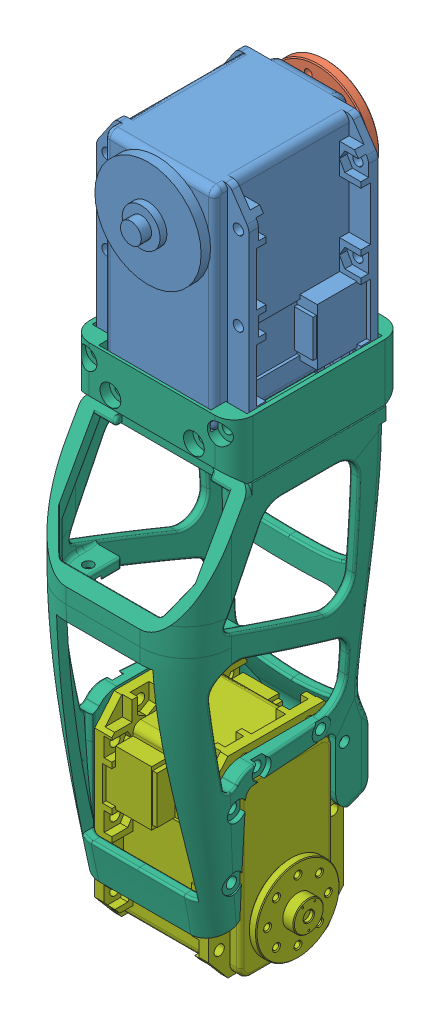
SolidWorks assembly arm_l2, configuration Default. Lengths in mm.
Overall size (45.99 187.91 62.65).
10 component instances, 10 part files, 20 mates.
Components (placement in the parent):
- MX-64T_step-1: MX-64T_step [Default] at (11.6566 50.7443 49.8736) size (40.2 62.1 50)
- HN05-I101_2017-1: HN05-I101_2017 [Default] at (11.6566 50.7443 26.3536) x (-0.978167 -0.207821 0) z (0.207821 -0.978167 0) size (28 3.8 28)
- MF128ZZ_2017-1: MF128ZZ_2017 [Default] at (11.6566 50.7443 30.0736) x (-0.981893 -0.189437 0) z (0.189437 -0.981893 0) size (14 3.48 14)
- RX64-CAP_2017-1: RX64-CAP_2017 [Default] at (11.6566 50.7443 26.5936) x (-0.772804 -0.634645 0) z (0 0 -1) size (9.5 9.5 2.2)
- WB_M2.5X8_2017-1: WB_M2.5X8_2017 [Default] at (11.6566 50.7443 24.2936) x (0 0 1) z (-0.923728 -0.383049 0) size (4.5 4.5 4.5)
- arm_upperarm-1: arm_upperarm [Default] at (-19.8184 -15.6443 22.4331) size (44.79 120.44 61.97)
- MX28_step-1: MX28_step [Default] at (-30.9345 -67.7118 42.6951) x (0 0 1) z (1 0 0) size (35.6 50.71 42.6)
- MX28_HN07-i101-1: MX28_HN07-i101 [Default] at (-8.5434 -105.0057 54.6029) x (0 0.707328 0.706886) z (0 -0.706886 0.707328) size (22 3.05 22)
- MF106ZZ-1: MF106ZZ [Défaut] at (-8.3934 -105.0057 54.6029) x (0 -0.837169 -0.546944) z (0 -0.546944 0.837169) size (11.2 3 11.2)
- RX28-CAP-1: RX28-CAP [Défaut] at (-8.3934 -105.0057 54.6029) x (0 0.357314 -0.933984) z (-1 0 0) size (7.2 7.2 1.8)
Mates (geometry in assembly coordinates):
- Concentric1: concentric aligned: cylinder of MX-64T_step-1 through (11.6566 50.7443 50.9736) axis (0 0 -1) radius 4; cylinder of HN05-I101_2017-1 through (11.6566 50.7443 26.3536) axis (0 0 -1) radius 6
- Coincident1: coincident aligned: cylinder of HN05-I101_2017-1 through (11.6566 50.7443 26.3536) axis (0 0 -1) radius 6; circle of MF128ZZ_2017-1
- Coincident2: coincident anti-aligned: plane of HN05-I101_2017-1 through (5.7876 49.4974 27.3536) normal (0 0 -1); plane of MF128ZZ_2017-1 through (4.7834 49.4183 27.3536) normal (0 0 1)
- Concentric2: concentric aligned: cylinder of MF128ZZ_2017-1 through (11.6566 50.7443 30.0736) axis (0 0 -1) radius 4; cylinder of RX64-CAP_2017-1 through (11.6566 50.7443 27.7936) axis (0 0 -1) radius 4
- Coincident3: coincident anti-aligned: plane of MF128ZZ_2017-1 through (7.7291 49.9866 26.5936) normal (0 0 -1); plane of RX64-CAP_2017-1 through (8.1017 47.825 26.5936) normal (0 0 1)
- Concentric3: concentric aligned: cylinder of RX64-CAP_2017-1 through (11.6566 50.7443 27.7936) axis (0 0 -1) radius 1.55; cylinder of WB_M2.5X8_2017-1 through (11.6566 50.7443 34.7936) axis (0 0 -1) radius 1.25
- Coincident4: coincident anti-aligned: plane of RX64-CAP_2017-1 through (10.3429 49.6654 26.7936) normal (0 0 -1); plane of WB_M2.5X8_2017-1 through (10.7948 52.8227 26.7936) normal (0 0 1)
- Coincident5: coincident anti-aligned: plane of MX-64T_step-1 through (11.6566 50.7443 30.0736) normal (0 0 -1); plane of MF128ZZ_2017-1 through (5.7653 49.6077 30.0736) normal (0 0 1)
- Concentric11: concentric anti-aligned: cylinder of MX-64T_step-1 through (-5.6434 10.7443 62.3736) axis (0 0 -1) radius 1.35; cylinder of arm_upperarm-1 through (-5.6434 10.7443 72.2736) axis (0 0 1) radius 2.75
- Concentric12: concentric anti-aligned: cylinder of MX-64T_step-1 through (0.6566 5.4443 49.8736) axis (0 0 -1) radius 1.35; cylinder of arm_upperarm-1 through (0.6566 5.4443 72.2736) axis (0 0 1) radius 2.75
- Distance3: distance = 0.8 mm anti-aligned: plane of MX-64T_step-1 through (11.6566 50.7443 66.8736) normal (0 0 1); plane of arm_upperarm-1 through (-8.7434 14.6443 67.6736) normal (0 0 -1)
- Concentric13: concentric anti-aligned: cylinder of arm_upperarm-1 through (36.8566 -69.2057 46.1029) axis (1 0 0) radius 1.35; cylinder of MX28_step-1 through (11.6566 -69.2057 46.1029) axis (-1 0 0) radius 1.35
- Concentric14: concentric anti-aligned: cylinder of arm_upperarm-1 through (36.8566 -69.2057 63.1029) axis (1 0 0) radius 1.35; cylinder of MX28_step-1 through (11.6566 -69.2057 63.1029) axis (-1 0 0) radius 1.35
- Coincident15: coincident aligned: plane of arm_upperarm-1 through (11.6566 -15.6443 22.4331) normal (1 0 0); plane of MX28_step-1 through (11.6566 -67.7118 42.6951) normal (1 0 0)
- Concentric15: concentric aligned: cylinder of MX28_HN07-i101-1 through (-8.6959 -105.0057 54.6029) axis (1 0 0) radius 5; cylinder of MF106ZZ-1 through (-8.3934 -105.0057 54.6029) axis (1 0 0) radius 5
- Coincident16: coincident anti-aligned: plane of MX28_HN07-i101-1 through (-7.7934 -105.0057 54.6029) normal (-1 0 0); plane of MF106ZZ-1 through (-7.7934 -109.1915 51.8681) normal (1 0 0)
- Concentric16: concentric anti-aligned: cylinder of MF106ZZ-1 through (-8.3934 -105.0057 54.6029) axis (1 0 0) radius 3; cylinder of RX28-CAP-1 through (-7.3934 -105.0057 54.6029) axis (-1 0 0) radius 3
- Coincident17: coincident anti-aligned: plane of MF106ZZ-1 through (-8.3934 -109.6938 51.54) normal (-1 0 0); plane of RX28-CAP-1 through (-8.3934 -103.7551 51.3339) normal (1 0 0)
- Concentric17: concentric anti-aligned: cylinder of MX28_step-1 through (12.6191 -105.0057 54.6029) axis (-1 0 0) radius 3; cylinder of MX28_HN07-i101-1 through (-8.6959 -105.0057 54.6029) axis (1 0 0) radius 6.25
- Coincident22: coincident anti-aligned: plane of MX28_step-1 through (-5.3934 -105.0057 54.6029) normal (-1 0 0); plane of MF106ZZ-1 through (-5.3934 -107.5172 52.962) normal (1 0 0)
